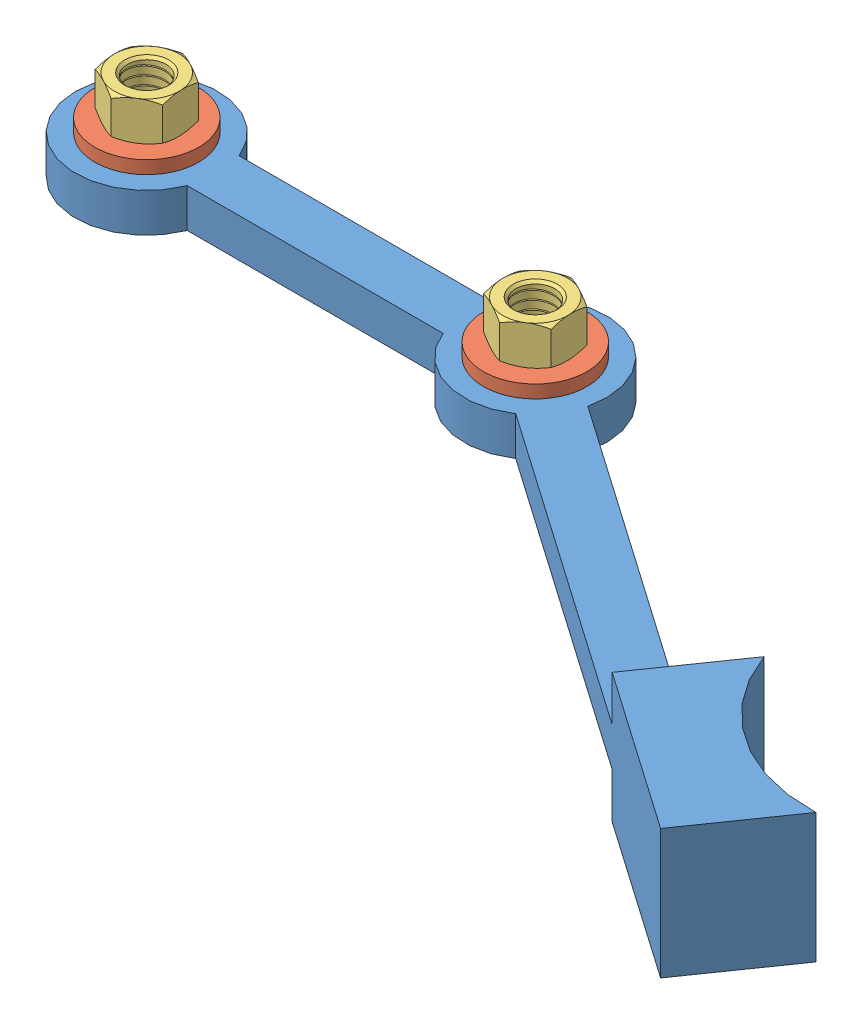
SolidWorks assembly Assem7_5, configuration Default. Lengths in mm.
Overall size (80.31 10.5 35.71).
5 component instances, 3 part files, 12 mates.
Components (placement in the parent):
- Part8-1: Part8 [Default] at origin size (80.31 10 35.71)
- sajbna8-1: sajbna8 [Default] at (30 1.5 0) size (8 1 8)
- sajbna8-2: sajbna8 [Default] at (0 1.5 0) size (8 1 8)
- navrtka7-1: navrtka7 [Default] at (30 4 0) x (1 0 0) z (0 1 0) size (5.57 5.77 3)
- navrtka7-2: navrtka7 [Default] at (0 4 0) x (1 0 0) z (0 1 0) size (5.57 5.77 3)
Mates (geometry in assembly coordinates):
- Concentric3: concentric anti-aligned: cylinder of Part8-1 through (30 -1.5 0) axis (0 1 0) radius 1.5; cylinder of sajbna8-1 through (30 2.5 0) axis (0 -1 0) radius 1.5
- Coincident3: coincident anti-aligned: plane of Part8-1 through (0 1.5 0) normal (0 1 0); plane of sajbna8-1 through (30 1.5 0) normal (0 -1 0)
- Concentric4: concentric anti-aligned: cylinder of Part8-1 through (0 -1.5 0) axis (0 1 0) radius 1.5; cylinder of sajbna8-2 through (0 2.5 0) axis (0 -1 0) radius 1.5
- Coincident4: coincident anti-aligned: plane of Part8-1 through (0 1.5 0) normal (0 1 0); plane of sajbna8-2 through (0 1.5 0) normal (0 -1 0)
- Concentric5: concentric anti-aligned: cylinder of Part8-1 through (30 -1.5 0) axis (0 1 0) radius 1.5; circle of navrtka7-1
- Coincident5: coincident anti-aligned: plane of sajbna8-1 through (30 2.5 0) normal (0 1 0); plane of navrtka7-1 through (30 2.5 0) normal (0 -1 0)
- Concentric6: concentric anti-aligned: cylinder of Part8-1 through (0 -1.5 0) axis (0 1 0) radius 1.5; circle of navrtka7-2
- Coincident6: coincident anti-aligned: plane of sajbna8-2 through (0 2.5 0) normal (0 1 0); plane of navrtka7-2 through (0 2.5 0) normal (0 -1 0)
- Parallel1: parallel aligned: plane of sajbna8-1 through (30 1.5 0) normal (0 0 1); plane of assembly through (0 0 0) normal (0 0 1)
- Parallel2: parallel aligned: plane of sajbna8-2 through (0 1.5 0) normal (0 0 1); plane of assembly through (0 0 0) normal (0 0 1)
- Parallel4: parallel anti-aligned: plane of navrtka7-1 through (30 4 0) normal (0 0 -1); plane of assembly
- Parallel5: parallel anti-aligned: plane of navrtka7-2 through (0 4 0) normal (0 0 -1); plane of assembly
